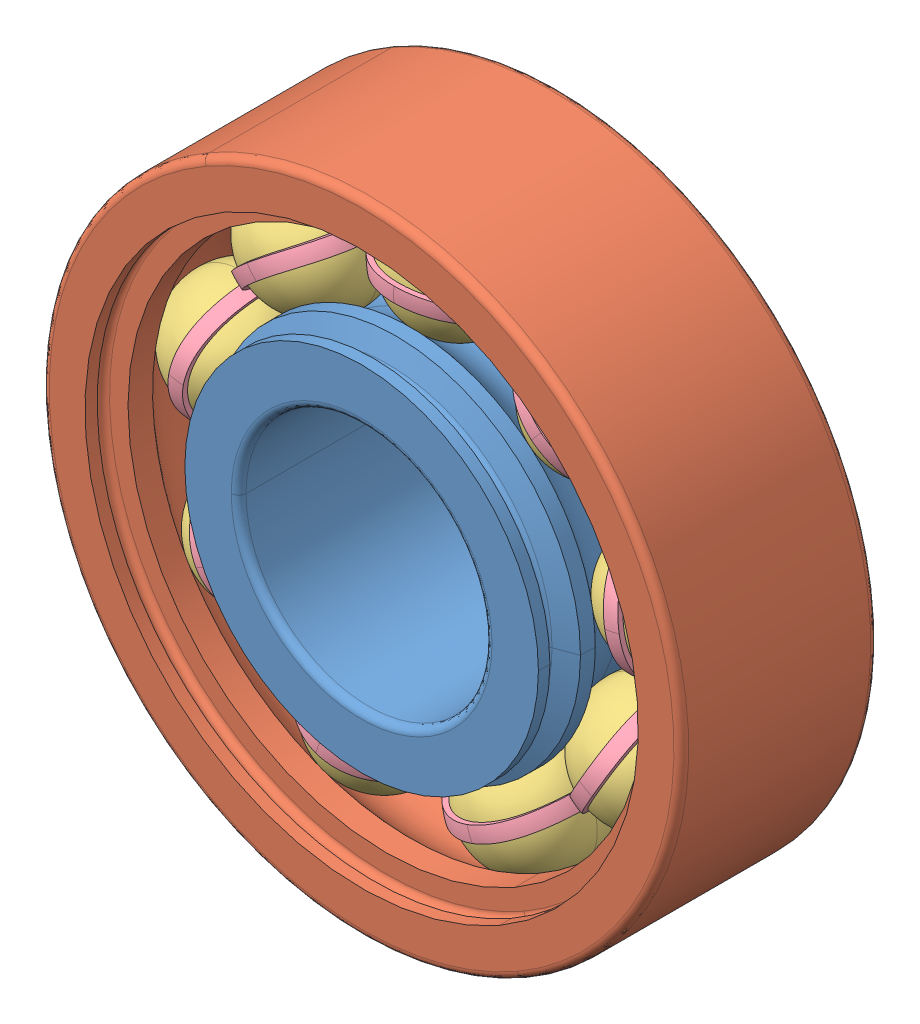
SolidWorks assembly Roulement, configuration Default. Lengths in mm.
Overall size (35.49 35.49 8).
13 component instances, 4 part files, 0 mates.
Components (placement in the parent):
- Roulement.STEP-1: Roulement.STEP [Default] at origin size (35.49 35.49 8)
  - bague interieure_type 6000.STEP-1: bague interieure_type 6000.STEP [Default] at origin size (15 15 8)
  - bague exterieure_type 6000.STEP-1: bague exterieure_type 6000.STEP [Default] x (0.497736 -0.867329 0) z (0 0 1) size (26 26 8)
  - Bille_type 6000.STEP-1: Bille_type 6000.STEP [Default] at (0 9 0) x (-1 0 0) z (0 0 -1) size (5 5 5)
  - cage_type 6000.STEP-1: cage_type 6000.STEP [Default] at origin size (19.26 18.97 5.41)
  - Bille_type 6000.STEP-2: Bille_type 6000.STEP [Default] at (-5.7851 6.8944 0) x (-0.766044 -0.642788 0) z (0 0 -1) size (5 5 5)
  - Bille_type 6000.STEP-3: Bille_type 6000.STEP [Default] at (-8.8633 1.5628 0) x (-0.173648 -0.984808 0) z (0 0 -1) size (5 5 5)
  - Bille_type 6000.STEP-4: Bille_type 6000.STEP [Default] at (-7.7942 -4.5 0) x (0.5 -0.866025 0) z (0 0 -1) size (5 5 5)
  - Bille_type 6000.STEP-5: Bille_type 6000.STEP [Default] at (-3.0782 -8.4572 0) x (0.939693 -0.34202 0) z (0 0 -1) size (5 5 5)
  - Bille_type 6000.STEP-6: Bille_type 6000.STEP [Default] at (3.0782 -8.4572 0) x (0.939693 0.34202 0) z (0 0 -1) size (5 5 5)
  - Bille_type 6000.STEP-7: Bille_type 6000.STEP [Default] at (7.7942 -4.5 0) x (0.5 0.866025 0) z (0 0 -1) size (5 5 5)
  - Bille_type 6000.STEP-8: Bille_type 6000.STEP [Default] at (8.8633 1.5628 0) x (-0.173648 0.984808 0) z (0 0 -1) size (5 5 5)
  - Bille_type 6000.STEP-9: Bille_type 6000.STEP [Default] at (5.7851 6.8944 0) x (-0.766044 0.642788 0) z (0 0 -1) size (5 5 5)
